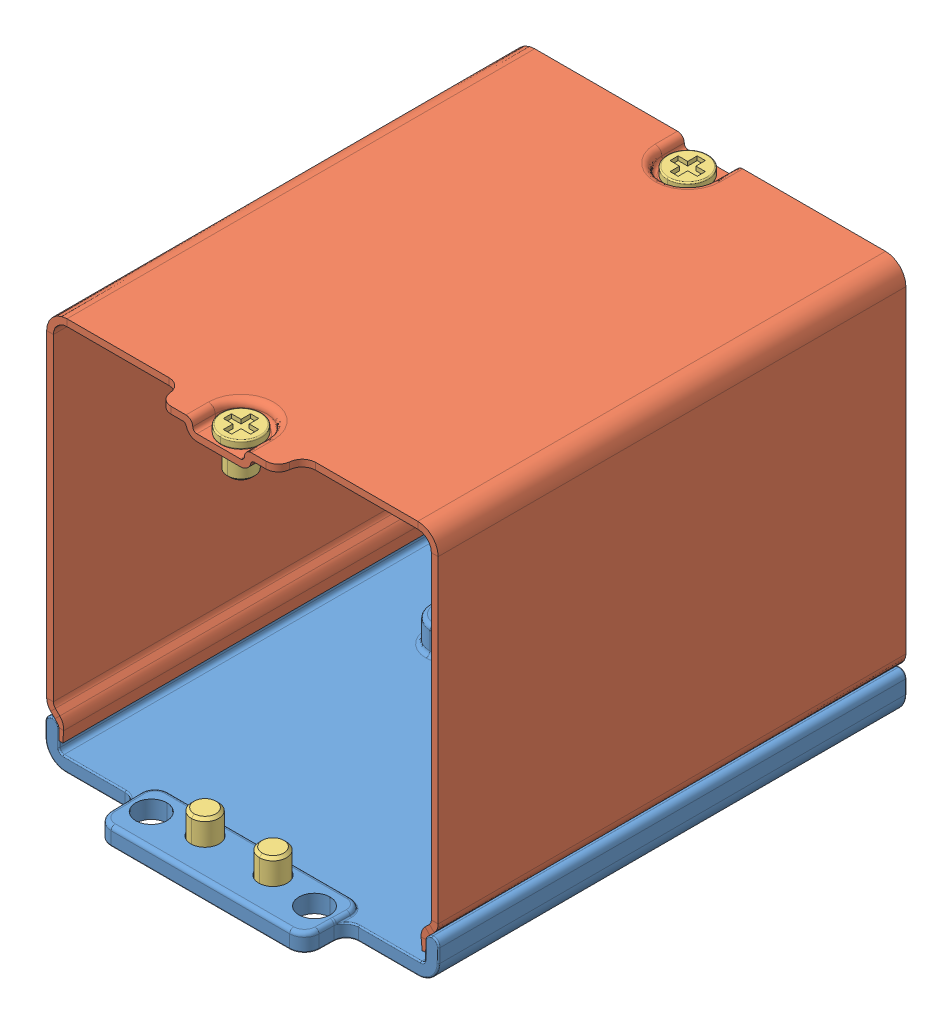
SolidWorks assembly Mako-G_C-Mount.STEP, configuration Default. Lengths in mm.
Overall size (29.3 29.09 39.35).
17 component instances, 8 part files, 0 mates.
Components (placement in the parent):
- Mako_FFL-ZDG-schwarz_CMV2-4000-LGA_C-Mount_montiert_STP-Erstellung.STEP-1: Mako_FFL-ZDG-schwarz_CMV2-4000-LGA_C-Mount_montiert_STP-Erstellung.STEP [Default] at origin
  - PCBA_MAKO-SB-CMV2-4000_LGA_STP-Erstellung.STEP-1: PCBA_MAKO-SB-CMV2-4000_LGA_STP-Erstellung.STEP [Default] at (0 0 3.25) x (-1 0 0) z (0 0 -1) (suppressed, hidden)
  - 11043-03_Mako_Frontflansch_ZDG_pulverlackiert_St_ckliste.STEP-1: 11043-03_Mako_Frontflansch_ZDG_pulverlackiert_St_ckliste.STEP [Default] at origin (suppressed, hidden)
  - 7691_Mako_Sensorauflage-CMV2000-4000-LGA_ZDG_St_ckliste.STEP-1: 7691_Mako_Sensorauflage-CMV2000-4000-LGA_ZDG_St_ckliste.STEP [Default] at (0 0 3.25) (suppressed, hidden)
  - 4473-4474-4475-4476-4477-4478-4479-4480-4481-4482-8275-8278-11274-11275-11276__Z05_Mako_Abstimmscheibe_St_ckliste.STEP-1: 4473-4474-4475-4476-4477-4478-4479-4480-4481-4482-8275-8278-11274-11275-11276__Z05_Mako_Abstimmscheibe_St_ckliste.STEP [Default] at (0 0 4.25) (suppressed, hidden)
- 12443_Mako-G_Rueckwand_montiert__Z03_CMVx-STP-Erstellung.STEP-1: 12443_Mako-G_Rueckwand_montiert__Z03_CMVx-STP-Erstellung.STEP [Default] at (0 0 -28.851)
  - K7600502_Kabelstecker-8polig-Stift_STP-Erstellung.STEP-1: K7600502_Kabelstecker-8polig-Stift_STP-Erstellung.STEP [Default] at (0.2033 0.2085 -0.1) x (0.999679 0.025323 0) z (0 0 1) (suppressed, hidden)
  - 11045-_Z03_Mako-G_Rueckwand_ZDG_pulverlackiert_St_ckliste.STEP-1: 11045-_Z03_Mako-G_Rueckwand_ZDG_pulverlackiert_St_ckliste.STEP [Default] at origin (suppressed, hidden)
  - 4589-MAKO-GIF-POE-GIGE_STP-Erstellung.STEP-1: 4589-MAKO-GIF-POE-GIGE_STP-Erstellung.STEP [Default] at (10.206 44.5002 33.0999) x (0 0 1) z (1 0 0) (suppressed, hidden)
- 11044-_Z02_Mako-G_Boden_ZDG_pulverlackiert_St_ckliste.STEP-1: 11044-_Z02_Mako-G_Boden_ZDG_pulverlackiert_St_ckliste.STEP [Default] at (0 -14.4 8.6491) size (29.3 3.19 39.35)
- 4605-_Z04_Mako-PoE_Deckel_nasslackiert+bedruckt_STP-Erstellung ohne Logos.STEP-1: 4605-_Z04_Mako-PoE_Deckel_nasslackiert+bedruckt_STP-Erstellung ohne Logos.STEP [Default] at (0 14 -11.65) size (28.8 27.19 36.15)
- 9533_Flachkopf-Schraube mit KS M2x2.4.STEP-1: 9533_Flachkopf-Schraube mit KS M2x2.4.STEP [Default] at (-0.4 -11.3 -28.6009) x (0 0 -1) z (0 1 0) size (3 3 3)
- 9533_Flachkopf-Schraube mit KS M2x2.4.STEP-2: 9533_Flachkopf-Schraube mit KS M2x2.4.STEP [Default] at (7.4 -11.3 -28.6009) x (0 0 -1) z (0 1 0) size (3 3 3)
- 9533_Flachkopf-Schraube mit KS M2x2.4.STEP-3: 9533_Flachkopf-Schraube mit KS M2x2.4.STEP [Default] at (0 11.3 5.65) x (0 0 1) z (0 -1 0) size (3 3 3)
- 9533_Flachkopf-Schraube mit KS M2x2.4.STEP-4: 9533_Flachkopf-Schraube mit KS M2x2.4.STEP [Default] at (0 11.3 -27.2) x (0 0 -1) z (0 -1 0) size (3 3 3)
- 9533_Flachkopf-Schraube mit KS M2x2.4.STEP-5: 9533_Flachkopf-Schraube mit KS M2x2.4.STEP [Default] at (-2.5 -11.3 5.7991) x (0 0 -1) z (0 1 0) size (3 3 3)
- 9533_Flachkopf-Schraube mit KS M2x2.4.STEP-6: 9533_Flachkopf-Schraube mit KS M2x2.4.STEP [Default] at (2.5 -11.3 5.7991) x (0 0 -1) z (0 1 0) size (3 3 3)
